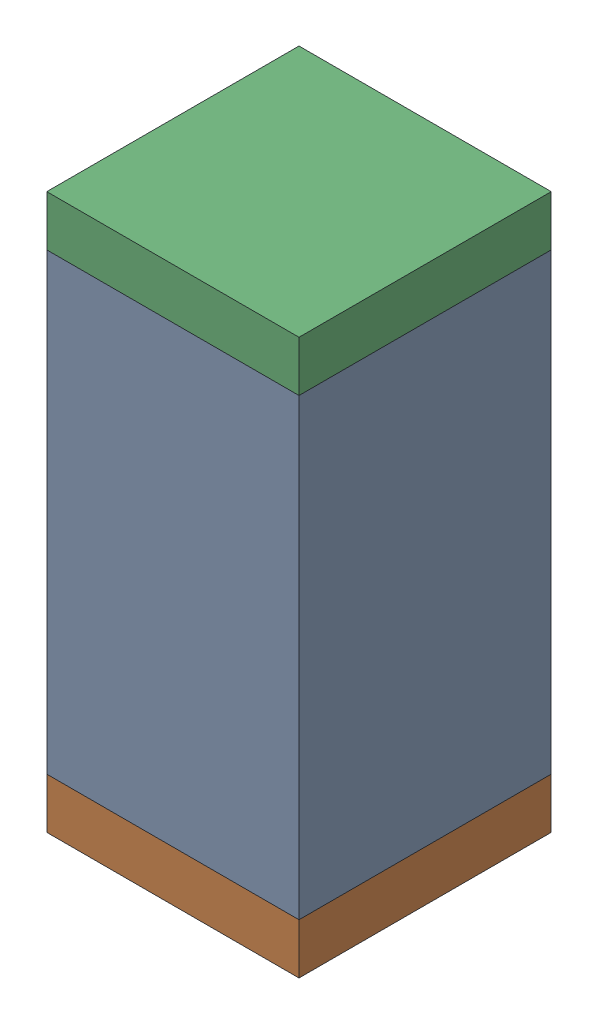
SolidWorks assembly C91, configuration Default. Lengths in mm.
Overall size (0.5 1.1 0.5).
6 component instances, 2 part files, 0 mates.
Components (placement in the parent):
- 791586336-1: 791586336 [Default] at (111.45 65.85 0) size (0.5 0.9 0.5)
  - Extruded_8-1: Extruded_8 [Default] at origin size (0.5 0.9 0.5)
- 810157360-1: 810157360 [Default] at (111.45 65.35 0) size (0.5 0.1 0.5)
  - Extruded_9-1: Extruded_9 [Default] at origin size (0.5 0.1 0.5)
- 810157360-2: 810157360 [Default] at (111.45 66.35 0) size (0.5 0.1 0.5)
  - Extruded_9-1: Extruded_9 [Default] at origin size (0.5 0.1 0.5)
